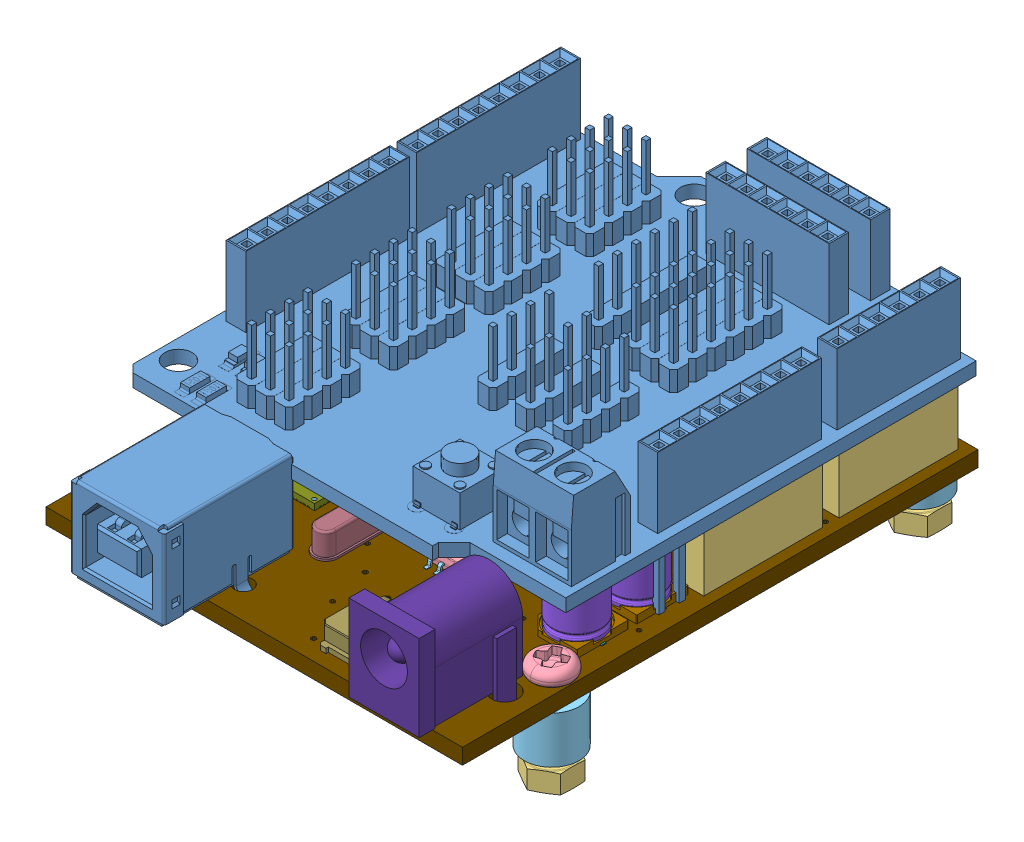
SolidWorks assembly ArduinoUnoWithSensorShield, configuration Predeterminado. Lengths in mm.
Overall size (54.69 31.54 75.71).
44 component instances, 23 part files, 19 mates.
Components (placement in the parent):
- Arduino Sensor Board V1-1: Arduino Sensor Board V1 [Predeterminado] at (-2.4496 -2.4606 58.16) size (53.65 20.91 58.16)
- ArduinoUno-1: ArduinoUno [Predeterminado] at (-77.0404 -6.9097 61.6865) x (0 0 -1) z (1 0 0) size (74.75 15.48 53.34)
  - Final-1: Final [Predeterminado] at (-36.0382 -5.851 101.423) size (74.75 15.48 53.34)
    - Stackable Female Pin Header_Default-1: Stackable Female Pin Header_Default [Predeterminado] at (23.9415 1.1201 -50.7298) size (20.32 8.3 2.54)
    - Stackable Female Pin Header_6 Way-1: Stackable Female Pin Header_6 Way [Predeterminado] at (33.5006 2 -2.5872) size (15.24 8.3 2.54)
    - User Library-SOIC-8_Default-1: User Library-SOIC-8_Default [Predeterminado] at (20.4108 1.85 -20.3024) x (0 0 -1) z (1 0 0) size (5 1.75 6.01)
      - User Library-SOIC-8_SOIC-8_Body_1_Default-1: User Library-SOIC-8_SOIC-8_Body_1_Default [Predeterminado] at origin size (5 1.6 4)
      - User Library-SOIC-8_SOIC-8_Pins_1_Default-1: User Library-SOIC-8_SOIC-8_Pins_1_Default [Predeterminado] at origin size (4.23 0.99 6.01)
    - User Library-ALU-D8_Default-1: User Library-ALU-D8_Default [Predeterminado] at (28.1214 1.8 -5.7935) x (0 0 -1) z (0 1 0) size (7 6.6 7.7)
      - User Library-ALU-D8_Pins_1_Default-1: User Library-ALU-D8_Pins_1_Default [Predeterminado] at origin size (7 0.65 0.4)
      - User Library-ALU-D8_Beschriftung_1_Default-1: User Library-ALU-D8_Beschriftung_1_Default [Predeterminado] at origin size (4.35 4.98 0.11)
      - User Library-ALU-D8_K_X_F6rper_1_Default-1: User Library-ALU-D8_K_X_F6rper_1_Default [Predeterminado] at origin size (6.3 6.3 7)
      - User Library-ALU-D8_Fuss_1_Default-1: User Library-ALU-D8_Fuss_1_Default [Predeterminado] at origin size (6.6 6.6 1)
    - User Library-ALU-D8_Default-2: User Library-ALU-D8_Default [Predeterminado] at (20.4464 1.8 -5.7935) x (0 0 -1) z (0 1 0) size (7 6.6 7.7)
      - User Library-ALU-D8_Pins_1_Default-1: User Library-ALU-D8_Pins_1_Default [Predeterminado] at origin size (7 0.65 0.4)
      - User Library-ALU-D8_Beschriftung_1_Default-1: User Library-ALU-D8_Beschriftung_1_Default [Predeterminado] at origin size (4.35 4.98 0.11)
      - User Library-ALU-D8_K_X_F6rper_1_Default-1: User Library-ALU-D8_K_X_F6rper_1_Default [Predeterminado] at origin size (6.3 6.3 7)
      - User Library-ALU-D8_Fuss_1_Default-1: User Library-ALU-D8_Fuss_1_Default [Predeterminado] at origin size (6.6 6.6 1)
    - Stackable Female Pin Header_Default-2: Stackable Female Pin Header_Default [Predeterminado] at (45.7158 1.1368 -50.806) size (20.32 8.3 2.54)
    - LED 1206_Default-1: LED 1206_Default [Predeterminado] at (28.1068 2 -36.9237) x (0 0 -1) z (1 0 0) size (1.6 1.1 3.2)
    - LED 1206_Default-2: LED 1206_Default [Predeterminado] at (58.3346 2 -36.8813) x (0 0 -1) z (1 0 0) size (1.6 1.1 3.2)
    - Header Vertical 2.54mm Pitch2_Header 6 Way-1: Header Vertical 2.54mm Pitch2_Header 6 Way [Predeterminado] at (62.2731 2 -29.1415) size (5.08 8.88 7.62)
    - SO 369A_Standard-1: SO 369A_Standard [Predeterminado] at (5.5398 2 -17.4191) x (0 0 -1) z (0 1 0) size (6.6 10.1 2.4)
    - Stackable Female Pin Header_6 Way-2: Stackable Female Pin Header_6 Way [Predeterminado] at (50.8347 2 -2.5872) size (15.24 8.3 2.54)
    - XTAL Small_Default-1: XTAL Small_Default [Predeterminado] at (14.2222 2 -30.4346) x (1 0 0) z (0 1 0) size (10.67 3.05 5.63)
    - LED 1206_Default-3: LED 1206_Default [Predeterminado] at (28.1068 2 -41.994) x (0 0 -1) z (1 0 0) size (1.6 1.1 3.2)
    - User Library-QFN32 (FTDI)_Default-1: User Library-QFN32 (FTDI)_Default [Predeterminado] at (19.2089 2.05 -38.1588) x (-1 0 0) z (0 1 0) size (5 5 0.81)
      - User Library-QFN32 (FTDI)_Beschriftung_1_Default-1: User Library-QFN32 (FTDI)_Beschriftung_1_Default [Predeterminado] at origin size (0.51 0.51 0.05)
      - User Library-QFN32 (FTDI)_Anschl_X_FCsse_1_Default-1: User Library-QFN32 (FTDI)_Anschl_X_FCsse_1_Default [Predeterminado] x (0 -1 0) z (0 0 1) size (3.86 0.12 0.12)
      - User Library-QFN32 (FTDI)_K_X_F6rper_1_Default-1: User Library-QFN32 (FTDI)_K_X_F6rper_1_Default [Predeterminado] at origin size (5 5 0.8)
    - User Library-dc range - dc connector[4840_2201]_Default-1: User Library-dc range - dc connector[4840_2201]_Default [Predeterminado] at (11.794 2 -12.8354) x (0 0 1) z (-1 0 0) size (9.51 14.5 13.83)
    - PCB_Final_Default-1: PCB_Final_Default [Predeterminado] at origin size (68.58 2 53.34)
    - LED 1206_Default-4: LED 1206_Default [Predeterminado] at (28.142 2 -34.2868) x (0 0 -1) z (1 0 0) size (1.6 1.1 3.2)
    - User Library-67068-0000-molex_Default-1: User Library-67068-0000-molex_Default [Predeterminado] at (-6.1546 2 -38.0545) x (0.002421 0 0.999997) z (-0.999997 0 0.002421) size (15.13 15.48 17)
    - IC DIP 28_Default-1: IC DIP 28_Default [Predeterminado] at (51.4233 4.3498 -16.4837) x (0 0.005002 0.999987) z (-1 0 0) size (7.87 6.22 35.94)
- M3 Nut-1: M3 Nut [Predeterminado] at (21.8426 -23.7606 83.7547) x (1 0 0) z (0 -1 0) size (6.27 6.27 2.71)
- M3x10 Philips Screw-1: M3x10 Philips Screw [Predeterminado] at (21.8426 -10.7606 83.7547) x (-0.88631 0 0.463093) z (0 1 0) size (5.3 5.3 11.8)
- separador-1: separador [Predeterminado] at (16.7626 -18.7606 31.6847) x (1 0 0) z (0 1 0) size (7 7 6)
- separador-2: separador [Predeterminado] at (-11.1774 -12.7606 31.6847) x (1 0 0) z (0 -1 0) size (7 7 6)
- separador-3: separador [Predeterminado] at (21.8426 -12.7606 83.7547) x (1 0 0) z (0 -1 0) size (7 7 6)
- M3x10 Philips Screw-2: M3x10 Philips Screw [Predeterminado] at (16.7626 -10.7606 31.6847) x (1 0 0) z (0 1 0) size (5.3 5.3 11.8)
- M3x10 Philips Screw-3: M3x10 Philips Screw [Predeterminado] at (-11.1774 -10.7606 31.6847) x (1 0 0) z (0 1 0) size (5.3 5.3 11.8)
- M3 Nut-2: M3 Nut [Predeterminado] at (16.7626 -23.7606 31.6847) x (1 0 0) z (0 -1 0) size (6.27 6.27 2.71)
- M3 Nut-3: M3 Nut [Predeterminado] at (-11.1774 -23.7606 31.6847) x (0.99989 0 -0.014845) z (0 -1 0) size (6.27 6.27 2.71)
Mates (geometry in assembly coordinates):
- Coincidente1: coincident: plane of Arduino Sensor Board V1-1 through (22.2954 -2.4606 33.69) normal (1 0 0); plane of ArduinoUno-1/Final-1/Stackable Female Pin Header_6 Way-2 through (22.2954 -6.4606 33.69) normal (-1 0 0)
- Coincidente2: coincident: plane of Arduino Sensor Board V1-1 through (21.4954 -2.4606 33.69) normal (0 0 -1); plane of ArduinoUno-1/Final-1/Stackable Female Pin Header_6 Way-2 through (22.2954 -6.4606 33.69) normal (0 0 1)
- Coincidente3: coincident: plane of Arduino Sensor Board V1-1 through (-2.4452 -2.4606 58.5355) normal (0 -1 0); plane of ArduinoUno-1/Final-1/Stackable Female Pin Header_6 Way-2 through (23.0654 -2.4606 48.16) normal (0 1 0)
- Coincidente4: coincident: plane of ArduinoUno-1/Final-1/PCB_Final_Default-1 through (-2.3058 -12.7606 131.309) normal (0 -1 0); plane of separador-1 through (16.7626 -12.7606 31.6847) normal (0 1 0)
- Concéntrica1: concentric: circle of ArduinoUno-1/Final-1/PCB_Final_Default-1; circle of separador-1
- Coincidente6: coincident: circle of ArduinoUno-1/Final-1/PCB_Final_Default-1; circle of separador-3
- Coincidente7: coincident: circle of ArduinoUno-1/Final-1/PCB_Final_Default-1; circle of separador-2
- Concéntrica2: concentric: circle of M3 Nut-1; circle of separador-3
- Distancia1: distance = 1 mm: plane of M3 Nut-1 through (21.8426 -19.7606 83.7547) normal (0 1 0); plane of separador-3 through (21.8426 -18.7606 83.7547) normal (0 -1 0)
- Concéntrica3: concentric: circle of ArduinoUno-1/Final-1/PCB_Final_Default-1; circle of M3x10 Philips Screw-1
- Coincidente9: coincident: plane of ArduinoUno-1/Final-1/PCB_Final_Default-1 through (-2.3058 -10.7606 131.309) normal (0 1 0); plane of M3x10 Philips Screw-1 through (22.5835 -10.7606 85.1728) normal (0 -1 0)
- Coincidente10: coincident: plane of ArduinoUno-1/Final-1/PCB_Final_Default-1 through (-2.3058 -10.7606 131.309) normal (0 1 0); plane of M3x10 Philips Screw-2 through (16.7626 -10.7606 30.0847) normal (0 -1 0)
- Concéntrica4: concentric: circle of ArduinoUno-1/Final-1/PCB_Final_Default-1; circle of M3x10 Philips Screw-2
- Coincidente11: coincident: plane of ArduinoUno-1/Final-1/PCB_Final_Default-1 through (-2.3058 -10.7606 131.309) normal (0 1 0); plane of M3x10 Philips Screw-3 through (-11.1774 -10.7606 30.0847) normal (0 -1 0)
- Concéntrica5: concentric: circle of ArduinoUno-1/Final-1/PCB_Final_Default-1; circle of M3x10 Philips Screw-3
- Distancia2: distance = 1 mm: plane of M3 Nut-2 through (16.7626 -19.7606 31.6847) normal (0 1 0); plane of separador-1 through (16.7626 -18.7606 31.6847) normal (0 -1 0)
- Concéntrica6: concentric: circle of separador-1; circle of M3 Nut-2
- Concéntrica7: concentric: circle of separador-2; circle of M3 Nut-3
- Distancia3: distance = 1 mm: plane of M3 Nut-3 through (-11.1774 -19.7606 31.6847) normal (0 1 0); plane of separador-2 through (-11.1774 -18.7606 31.6847) normal (0 -1 0)
